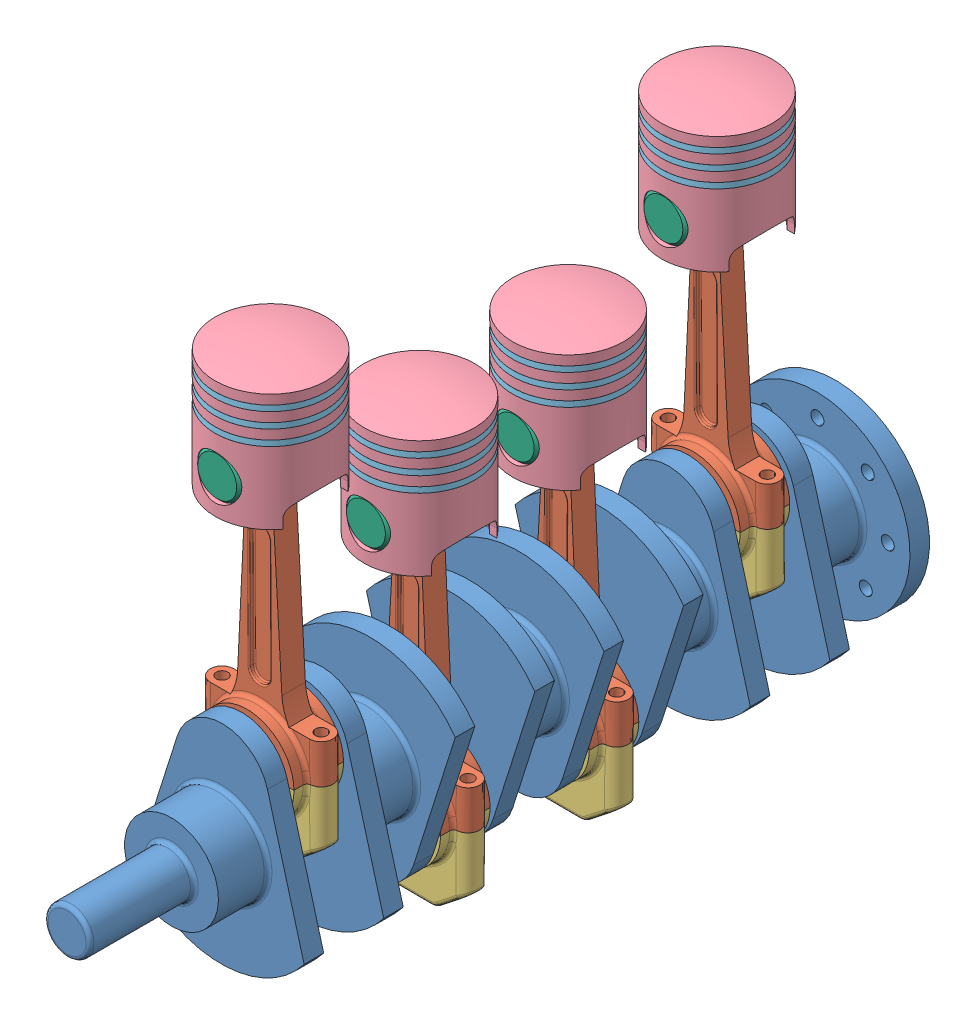
SolidWorks assembly Engine 2003072, configuration Default. Lengths in mm.
Overall size (147.06 418.41 589).
29 component instances, 6 part files, 66 mates.
Components (placement in the parent):
- Crankshaft-1: Crankshaft [Default] at (0 0 456) x (-0.999814 0.019293 0) z (0 0 1) size (144 160 589)
- Connecting rod-1: Connecting rod [Default] at (0 245.19 433) x (0.999991 0.004219 0) z (0 0 1) size (94 223.7 38)
- Connecting rod cap-1: Connecting rod cap [Default] at (0.8489 43.9918 433) x (-0.999991 -0.004219 0) z (0 0 1) size (94 60 38)
- Piston-1: Piston [Default] at (0 219.2199 433) size (85 95 85)
- Piston ring-1: Piston ring [Default] at (0 297.6199 433) size (85 4.3 85)
- Piston Pin-1: Piston Pin [Default] at (0 245.19 433) size (33.8 33.8 82)
- Piston ring-2: Piston ring [Default] at (0 286.0199 433) x (0.546944 0 -0.837169) z (0.837169 0 0.546944) size (85 4.3 85)
- Piston ring-4: Piston ring [Default] at (0 274.4199 433) x (0.546944 0 -0.837169) z (0.837169 0 0.546944) size (85 4.3 85)
- Piston-2: Piston [Default] at (0 131.2362 319) size (85 95 85)
- Piston ring-6: Piston ring [Default] at (0 209.6362 319) x (0.941458 0 -0.337131) z (0.337131 0 0.941458) size (85 4.3 85)
- Piston ring-7: Piston ring [Default] at (0 198.0362 319) x (0.23269 0 -0.972551) z (0.972551 0 0.23269) size (85 4.3 85)
- Piston ring-8: Piston ring [Default] at (0 186.4362 319) x (0.23269 0 -0.972551) z (0.972551 0 0.23269) size (85 4.3 85)
- Piston Pin-2: Piston Pin [Default] at (0 157.2064 319) x (0.216826 -0.97621 0) z (0 0 1) size (33.8 33.8 82)
- Connecting rod-2: Connecting rod [Default] at (0 157.2064 319) x (0.999991 -0.004219 0) z (0 0 1) size (94 223.7 38)
- Connecting rod cap-2: Connecting rod cap [Default] at (-0.8489 -43.9918 319) x (-0.999991 0.004219 0) z (0 0 1) size (94 60 38)
- Piston-4: Piston [Default] at (0 131.2362 205) x (-1 0 0) z (0 0 -1) size (85 95 85)
- Piston ring-12: Piston ring [Default] at (0 209.6362 205) x (0.790546 0 -0.612403) z (0.612403 0 0.790546) size (85 4.3 85)
- Piston ring-13: Piston ring [Default] at (0 198.0362 205) x (-0.0803 0 -0.996771) z (0.996771 0 -0.0803) size (85 4.3 85)
- Piston ring-14: Piston ring [Default] at (0 186.4362 205) x (-0.0803 0 -0.996771) z (0.996771 0 -0.0803) size (85 4.3 85)
- Piston Pin-4: Piston Pin [Default] at (0 157.2064 205) x (-0.34202 0.939693 0) z (0 0 -1) size (33.8 33.8 82)
- Connecting rod-4: Connecting rod [Default] at (0 157.2064 205) x (-0.999991 0.004219 0) z (0 0 -1) size (94 223.7 38)
- Connecting rod cap-4: Connecting rod cap [Default] at (-0.8489 -43.9918 205) x (0.999991 -0.004219 0) z (0 0 -1) size (94 60 38)
- Piston-6: Piston [Default] at (0 219.2199 91) x (-1 0 0) z (0 0 -1) size (85 95 85)
- Piston ring-18: Piston ring [Default] at (0 297.6199 91) x (0.6 0 -0.8) z (0.8 0 0.6) size (85 4.3 85)
- Piston ring-19: Piston ring [Default] at (0 286.0199 91) x (-0.341569 0 -0.939857) z (0.939857 0 -0.341569) size (85 4.3 85)
- Piston ring-20: Piston ring [Default] at (0 274.4199 91) x (-0.341569 0 -0.939857) z (0.939857 0 -0.341569) size (85 4.3 85)
- Piston Pin-6: Piston Pin [Default] at (0 245.19 91) x (-0.5 0.866025 0) z (0 0 -1) size (33.8 33.8 82)
- Connecting rod-6: Connecting rod [Default] at (0 245.19 91) x (-0.999991 -0.004219 0) z (0 0 -1) size (94 223.7 38)
- Connecting rod cap-6: Connecting rod cap [Default] at (0.8489 43.9918 91) x (0.999991 0.004219 0) z (0 0 -1) size (94 60 38)
Mates (geometry in assembly coordinates):
- Concentric1: concentric anti-aligned: cylinder of Crankshaft-1 through (0 0 589) axis (0 0 -1) radius 17.5
- Coincident1: coincident: plane of Crankshaft-1 through (0 0 589) normal (0 0 1)
- Coincident2: coincident aligned: plane of Piston-1 through (0 219.2199 433) normal (0 0 1); plane of Piston Pin-1 through (0 245.19 433) normal (0 0 1)
- Concentric2: concentric anti-aligned: cylinder of Piston-1 through (0 245.19 390.5) axis (0 0 1) radius 16.9; cylinder of Piston Pin-1 through (0 245.19 474) axis (0 0 -1) radius 16.9
- Concentric3: concentric aligned: cylinder of Piston-1 through (0 309.2199 433) axis (0 -1 0) radius 42.5; cylinder of Piston ring-1 through (0 301.9199 433) axis (0 -1 0) radius 42.5
- Coincident3: coincident anti-aligned: plane of Piston-1 through (0 297.6199 433) normal (0 1 0); plane of Piston ring-1 through (0 297.6199 433) normal (0 -1 0)
- Concentric4: concentric anti-aligned: cylinder of Piston-1 through (0 286.0199 433) axis (0 1 0) radius 39.5; cylinder of Piston ring-2 through (0 290.3199 433) axis (0 -1 0) radius 42.5
- Coincident4: coincident anti-aligned: plane of Piston-1 through (0 286.0199 433) normal (0 1 0); plane of Piston ring-2 through (0 286.0199 433) normal (0 -1 0)
- Concentric5: concentric anti-aligned: cylinder of Piston-1 through (0 274.4199 433) axis (0 1 0) radius 39.5; cylinder of Piston ring-4 through (0 278.7199 433) axis (0 -1 0) radius 42.5
- Coincident5: coincident anti-aligned: plane of Piston-1 through (0 274.4199 433) normal (0 1 0); plane of Piston ring-4 through (0 274.4199 433) normal (0 -1 0)
- Coincident6: coincident aligned: plane of Connecting rod-1 through (0 245.19 433) normal (0 0 1); plane of Piston-1 through (0 219.2199 433) normal (0 0 1)
- Concentric6: concentric aligned: cylinder of Connecting rod-1 through (0 245.19 452) axis (0 0 -1) radius 16.9; cylinder of Piston Pin-1 through (0 245.19 474) axis (0 0 -1) radius 16.9
- Concentric7: concentric aligned: cylinder of Connecting rod-1 through (38.8486 44.1521 433) axis (-0.004219 0.999991 0) radius 4.5; cylinder of Connecting rod cap-1 through (39.1017 -15.8473 433) axis (-0.004219 0.999991 0) radius 4.5
- Concentric8: concentric aligned: cylinder of Connecting rod-1 through (-37.1508 43.8315 433) axis (-0.004219 0.999991 0) radius 4.5; cylinder of Connecting rod cap-1 through (-36.8976 -16.168 433) axis (-0.004219 0.999991 0) radius 4.5
- Coincident7: coincident anti-aligned: plane of Connecting rod-1 through (0.8489 43.9918 452) normal (0.004219 -0.999991 0); plane of Connecting rod cap-1 through (36.8486 44.1437 452) normal (-0.004219 0.999991 0)
- Width1: width anti-aligned: plane of Crankshaft-1 through (0 0 410) normal (0 0 1); plane of Crankshaft-1 through (0 0 456) normal (0 0 -1); plane of Connecting rod-1 through (0 245.19 424) normal (0 0 -1); plane of Connecting rod-1 through (0 245.19 442) normal (0 0 1)
- Concentric9: concentric anti-aligned: cylinder of Crankshaft-1 through (0.8489 43.9918 410) axis (0 0 1) radius 27; cylinder of Connecting rod-1 through (0.8489 43.9918 452) axis (0 0 -1) radius 27
- Concentric10: concentric anti-aligned: cylinder of Piston-1 through (0 309.2199 433) axis (0 -1 0) radius 42.5
- Coincident9: coincident aligned: plane of Piston-2 through (0 131.2362 319) normal (0 0 1); plane of Piston Pin-2 through (0 157.2064 319) normal (0 0 1)
- Concentric11: concentric anti-aligned: cylinder of Piston-2 through (0 157.2064 276.5) axis (0 0 1) radius 16.9; cylinder of Piston Pin-2 through (0 157.2064 360) axis (0 0 -1) radius 16.9
- Concentric12: concentric aligned: cylinder of Piston-2 through (0 221.2362 319) axis (0 -1 0) radius 42.5; cylinder of Piston ring-6 through (0 213.9362 319) axis (0 -1 0) radius 42.5
- Coincident10: coincident anti-aligned: plane of Piston-2 through (0 209.6362 319) normal (0 1 0); plane of Piston ring-6 through (0 209.6362 319) normal (0 -1 0)
- Concentric13: concentric anti-aligned: cylinder of Piston-2 through (0 198.0362 319) axis (0 1 0) radius 39.5; cylinder of Piston ring-7 through (0 202.3362 319) axis (0 -1 0) radius 42.5
- Coincident11: coincident anti-aligned: plane of Piston-2 through (0 198.0362 319) normal (0 1 0); plane of Piston ring-7 through (0 198.0362 319) normal (0 -1 0)
- Concentric14: concentric anti-aligned: cylinder of Piston-2 through (0 186.4362 319) axis (0 1 0) radius 39.5; cylinder of Piston ring-8 through (0 190.7362 319) axis (0 -1 0) radius 42.5
- Coincident12: coincident anti-aligned: plane of Piston-2 through (0 186.4362 319) normal (0 1 0); plane of Piston ring-8 through (0 186.4362 319) normal (0 -1 0)
- Coincident13: coincident aligned: plane of Piston-2 through (0 131.2362 319) normal (0 0 1); plane of Connecting rod-2 through (0 157.2064 319) normal (0 0 1)
- Concentric15: concentric aligned: cylinder of Piston Pin-2 through (0 157.2064 360) axis (0 0 -1) radius 16.9; cylinder of Connecting rod-2 through (0 157.2064 338) axis (0 0 -1) radius 16.9
- Concentric16: concentric aligned: cylinder of Connecting rod-2 through (37.1508 -44.1521 319) axis (0.004219 0.999991 0) radius 4.5; cylinder of Connecting rod cap-2 through (36.8976 -104.1516 319) axis (0.004219 0.999991 0) radius 4.5
- Concentric17: concentric aligned: cylinder of Connecting rod-2 through (-38.8486 -43.8315 319) axis (0.004219 0.999991 0) radius 4.5; cylinder of Connecting rod cap-2 through (-39.1017 -103.8309 319) axis (0.004219 0.999991 0) radius 4.5
- Coincident14: coincident anti-aligned: plane of Connecting rod-2 through (-0.8489 -43.9918 338) normal (-0.004219 -0.999991 0); plane of Connecting rod cap-2 through (35.1508 -44.1437 338) normal (0.004219 0.999991 0)
- Width2: width anti-aligned: plane of Crankshaft-1 through (0 0 342) normal (0 0 -1); plane of Crankshaft-1 through (0 0 296) normal (0 0 1); plane of Connecting rod-2 through (0 157.2064 310) normal (0 0 -1); plane of Connecting rod-2 through (0 157.2064 328) normal (0 0 1)
- Concentric18: concentric anti-aligned: cylinder of Crankshaft-1 through (-0.8489 -43.9918 296) axis (0 0 1) radius 27; cylinder of Connecting rod-2 through (-0.8489 -43.9918 338) axis (0 0 -1) radius 27
- Concentric19: concentric anti-aligned: cylinder of Piston-2 through (0 221.2362 319) axis (0 -1 0) radius 42.5
- Coincident21: coincident aligned: plane of Piston-4 through (0 131.2362 205) normal (0 0 -1); plane of Piston Pin-4 through (0 157.2064 205) normal (0 0 -1)
- Concentric27: concentric anti-aligned: cylinder of Piston-4 through (0 157.2064 247.5) axis (0 0 -1) radius 16.9; cylinder of Piston Pin-4 through (0 157.2064 164) axis (0 0 1) radius 16.9
- Concentric28: concentric aligned: cylinder of Piston-4 through (0 221.2362 205) axis (0 -1 0) radius 42.5; cylinder of Piston ring-12 through (0 213.9362 205) axis (0 -1 0) radius 42.5
- Coincident22: coincident anti-aligned: plane of Piston-4 through (0 209.6362 205) normal (0 1 0); plane of Piston ring-12 through (0 209.6362 205) normal (0 -1 0)
- Concentric29: concentric anti-aligned: cylinder of Piston-4 through (0 198.0362 205) axis (0 1 0) radius 39.5; cylinder of Piston ring-13 through (0 202.3362 205) axis (0 -1 0) radius 42.5
- Coincident23: coincident anti-aligned: plane of Piston-4 through (0 198.0362 205) normal (0 1 0); plane of Piston ring-13 through (0 198.0362 205) normal (0 -1 0)
- Concentric30: concentric anti-aligned: cylinder of Piston-4 through (0 186.4362 205) axis (0 1 0) radius 39.5; cylinder of Piston ring-14 through (0 190.7362 205) axis (0 -1 0) radius 42.5
- Coincident24: coincident anti-aligned: plane of Piston-4 through (0 186.4362 205) normal (0 1 0); plane of Piston ring-14 through (0 186.4362 205) normal (0 -1 0)
- Coincident25: coincident aligned: plane of Piston-4 through (0 131.2362 205) normal (0 0 -1); plane of Connecting rod-4 through (0 157.2064 205) normal (0 0 -1)
- Concentric31: concentric aligned: cylinder of Piston Pin-4 through (0 157.2064 164) axis (0 0 1) radius 16.9; cylinder of Connecting rod-4 through (0 157.2064 186) axis (0 0 1) radius 16.9
- Concentric32: concentric aligned: cylinder of Connecting rod-4 through (-38.8486 -43.8315 205) axis (0.004219 0.999991 0) radius 4.5; cylinder of Connecting rod cap-4 through (-39.1017 -103.8309 205) axis (0.004219 0.999991 0) radius 4.5
- Concentric33: concentric aligned: cylinder of Connecting rod-4 through (37.1508 -44.1521 205) axis (0.004219 0.999991 0) radius 4.5; cylinder of Connecting rod cap-4 through (36.8976 -104.1516 205) axis (0.004219 0.999991 0) radius 4.5
- Coincident26: coincident anti-aligned: plane of Connecting rod-4 through (-0.8489 -43.9918 186) normal (-0.004219 -0.999991 0); plane of Connecting rod cap-4 through (-36.8486 -43.8399 186) normal (0.004219 0.999991 0)
- Width3: width anti-aligned: plane of Crankshaft-1 through (0 0 228) normal (0 0 -1); plane of Crankshaft-1 through (0 0 182) normal (0 0 1); plane of Connecting rod-4 through (0 157.2064 214) normal (0 0 1); plane of Connecting rod-4 through (0 157.2064 196) normal (0 0 -1)
- Concentric34: concentric anti-aligned: cylinder of Crankshaft-1 through (-0.8489 -43.9918 228) axis (0 0 -1) radius 27; cylinder of Connecting rod-4 through (-0.8489 -43.9918 186) axis (0 0 1) radius 27
- Concentric35: concentric anti-aligned: cylinder of Piston-4 through (0 221.2362 205) axis (0 -1 0) radius 42.5
- Coincident33: coincident aligned: plane of Piston-6 through (0 219.2199 91) normal (0 0 -1); plane of Piston Pin-6 through (0 245.19 91) normal (0 0 -1)
- Concentric43: concentric anti-aligned: cylinder of Piston-6 through (0 245.19 133.5) axis (0 0 -1) radius 16.9; cylinder of Piston Pin-6 through (0 245.19 50) axis (0 0 1) radius 16.9
- Concentric44: concentric aligned: cylinder of Piston-6 through (0 309.2199 91) axis (0 -1 0) radius 42.5; cylinder of Piston ring-18 through (0 301.9199 91) axis (0 -1 0) radius 42.5
- Coincident34: coincident anti-aligned: plane of Piston-6 through (0 297.6199 91) normal (0 1 0); plane of Piston ring-18 through (0 297.6199 91) normal (0 -1 0)
- Concentric45: concentric anti-aligned: cylinder of Piston-6 through (0 286.0199 91) axis (0 1 0) radius 39.5; cylinder of Piston ring-19 through (0 290.3199 91) axis (0 -1 0) radius 42.5
- Coincident35: coincident anti-aligned: plane of Piston-6 through (0 286.0199 91) normal (0 1 0); plane of Piston ring-19 through (0 286.0199 91) normal (0 -1 0)
- Concentric46: concentric anti-aligned: cylinder of Piston-6 through (0 274.4199 91) axis (0 1 0) radius 39.5; cylinder of Piston ring-20 through (0 278.7199 91) axis (0 -1 0) radius 42.5
- Coincident36: coincident anti-aligned: plane of Piston-6 through (0 274.4199 91) normal (0 1 0); plane of Piston ring-20 through (0 274.4199 91) normal (0 -1 0)
- Coincident37: coincident aligned: plane of Piston-6 through (0 219.2199 91) normal (0 0 -1); plane of Connecting rod-6 through (0 245.19 91) normal (0 0 -1)
- Concentric47: concentric aligned: cylinder of Piston Pin-6 through (0 245.19 50) axis (0 0 1) radius 16.9; cylinder of Connecting rod-6 through (0 245.19 72) axis (0 0 1) radius 16.9
- Concentric48: concentric aligned: cylinder of Connecting rod-6 through (-37.1508 43.8315 91) axis (-0.004219 0.999991 0) radius 4.5; cylinder of Connecting rod cap-6 through (-36.8976 -16.168 91) axis (-0.004219 0.999991 0) radius 4.5
- Concentric49: concentric aligned: cylinder of Connecting rod-6 through (38.8486 44.1521 91) axis (-0.004219 0.999991 0) radius 4.5; cylinder of Connecting rod cap-6 through (39.1017 -15.8473 91) axis (-0.004219 0.999991 0) radius 4.5
- Coincident38: coincident anti-aligned: plane of Connecting rod-6 through (0.8489 43.9918 72) normal (0.004219 -0.999991 0); plane of Connecting rod cap-6 through (-35.1508 43.8399 72) normal (-0.004219 0.999991 0)
- Width4: width anti-aligned: plane of Crankshaft-1 through (0 0 114) normal (0 0 -1); plane of Crankshaft-1 through (0 0 68) normal (0 0 1); plane of Connecting rod-6 through (0 245.19 100) normal (0 0 1); plane of Connecting rod-6 through (0 245.19 82) normal (0 0 -1)
- Concentric50: concentric anti-aligned: cylinder of Crankshaft-1 through (0.8489 43.9918 114) axis (0 0 -1) radius 27; cylinder of Connecting rod-6 through (0.8489 43.9918 72) axis (0 0 1) radius 27
- Concentric51: concentric anti-aligned: cylinder of Piston-6 through (0 309.2199 91) axis (0 -1 0) radius 42.5
